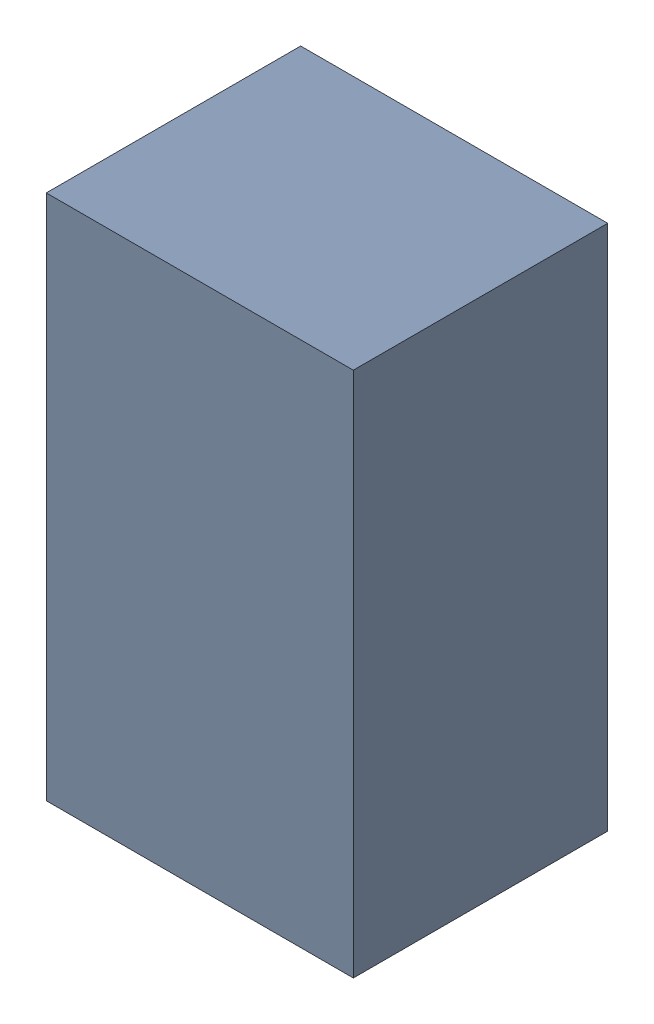
SolidWorks assembly U1-1, configuration Default. Lengths in mm.
Overall size (1.75 3 1.45).
2 component instances, 1 part files, 0 mates.
Components (placement in the parent):
- 959209616-1-1: 959209616-1 [Default] at (137.668 84.449 0) size (1.75 3 1.45)
  - Extruded-58-1: Extruded-58 [Default] at origin size (1.75 3 1.45)
